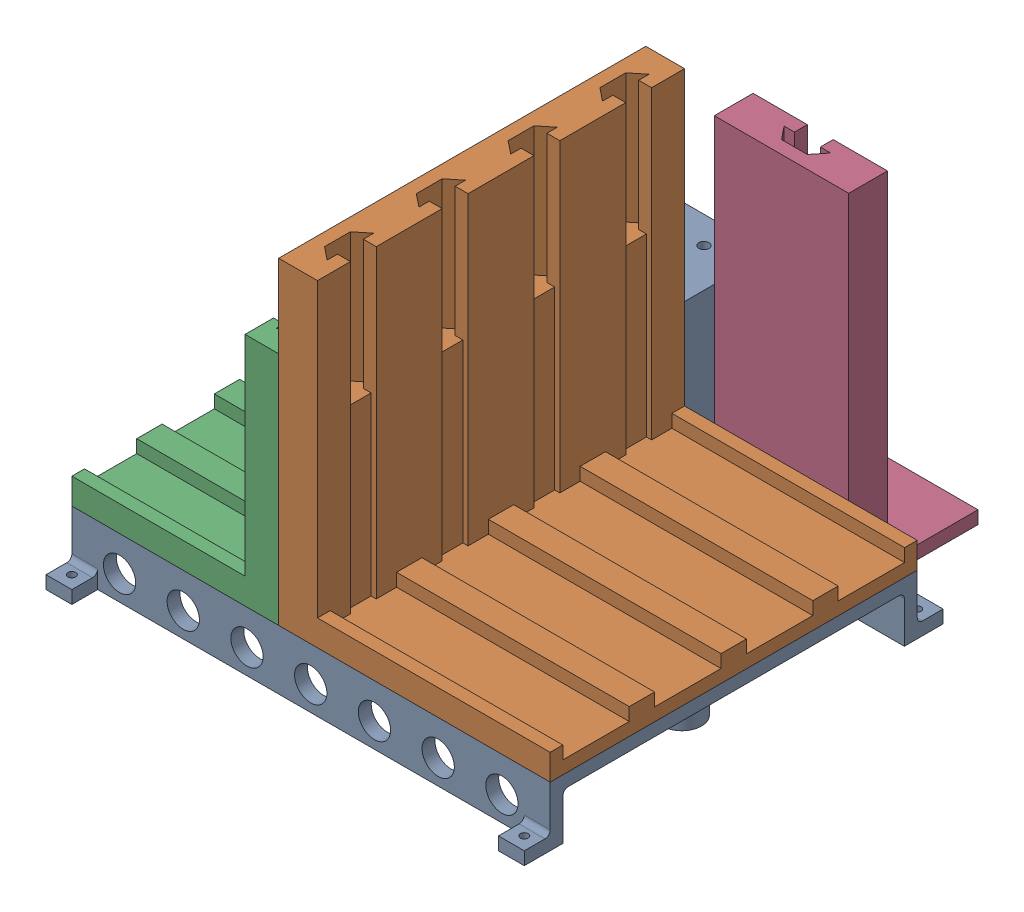
SolidWorks assembly FinalDriverHolder, configuration Default. Lengths in mm.
Overall size (185 146 210).
4 component instances, 4 part files, 9 mates.
Components (placement in the parent):
- NewAviatorFrame (1)-1: NewAviatorFrame (1) [Default] at (-91.3571 -48.3375 109.2329) size (185 53 210)
- DM542Frame-1: DM542Frame [Default] at (41.1429 -25.3375 91.4829) x (0 0 1) z (-1 0 0) size (142 123 105)
- DM320Frame-1: DM320Frame [Default] at (-51.3571 -25.3375 34.2329) x (0 0 -1) z (1 0 0) size (90 91 80)
- TeensyFrame-1: TeensyFrame [Default] at (41.1429 -48.3375 -57.7671) x (-1 0 0) z (0 0 -1) size (52 136 50)
Mates (geometry in assembly coordinates):
- Coincident1: coincident anti-aligned: plane of NewAviatorFrame (1)-1 through (-91.3571 -25.3375 109.2329) normal (0 1 0); plane of DM542Frame-1 through (41.1429 -25.3375 91.4829) normal (0 -1 0)
- Coincident2: coincident aligned: plane of NewAviatorFrame (1)-1 through (-91.3571 -25.3375 109.2329) normal (0 0 1); plane of DM542Frame-1 through (-11.3571 -15.3375 109.2329) normal (0 0 1)
- Coincident3: coincident anti-aligned: plane of NewAviatorFrame (1)-1 through (-11.3571 4.6625 19.2329) normal (1 0 0); plane of DM542Frame-1 through (-11.3571 -15.3375 73.7329) normal (-1 0 0)
- Coincident4: coincident anti-aligned: plane of NewAviatorFrame (1)-1 through (-91.3571 -25.3375 109.2329) normal (0 1 0); plane of DM320Frame-1 through (-51.3571 -25.3375 34.2329) normal (0 -1 0)
- Coincident5: coincident anti-aligned: plane of DM542Frame-1 through (-11.3571 -15.3375 73.7329) normal (-1 0 0); plane of DM320Frame-1 through (-11.3571 -15.3375 49.2329) normal (1 0 0)
- Coincident6: coincident aligned: plane of NewAviatorFrame (1)-1 through (-91.3571 -25.3375 109.2329) normal (0 0 1); plane of DM320Frame-1 through (-11.3571 -15.3375 109.2329) normal (0 0 1)
- Coincident8: coincident: plane of NewAviatorFrame (1)-1 through (-91.3571 -25.3375 -32.7671) normal (0 0 -1); plane of TeensyFrame-1 through (67.1429 -43.3375 -32.7671) normal (0 0 1)
- Coincident9: coincident: plane of NewAviatorFrame (1)-1 through (-91.3571 -48.3375 109.2329) normal (0 -1 0); plane of TeensyFrame-1 through (41.1429 -48.3375 -57.7671) normal (0 -1 0)
- Width1: width aligned: plane of TeensyFrame-1 through (67.1429 -43.3375 -82.7671) normal (1 0 0); plane of NewAviatorFrame (1)-1 through (15.1429 -43.3375 -82.7671) normal (-1 0 0); plane of TeensyFrame-1 through (-1.3571 -48.3375 -42.7671) normal (1 0 0); plane of NewAviatorFrame (1)-1 through (83.6429 -48.3375 -42.7671) normal (-1 0 0)
